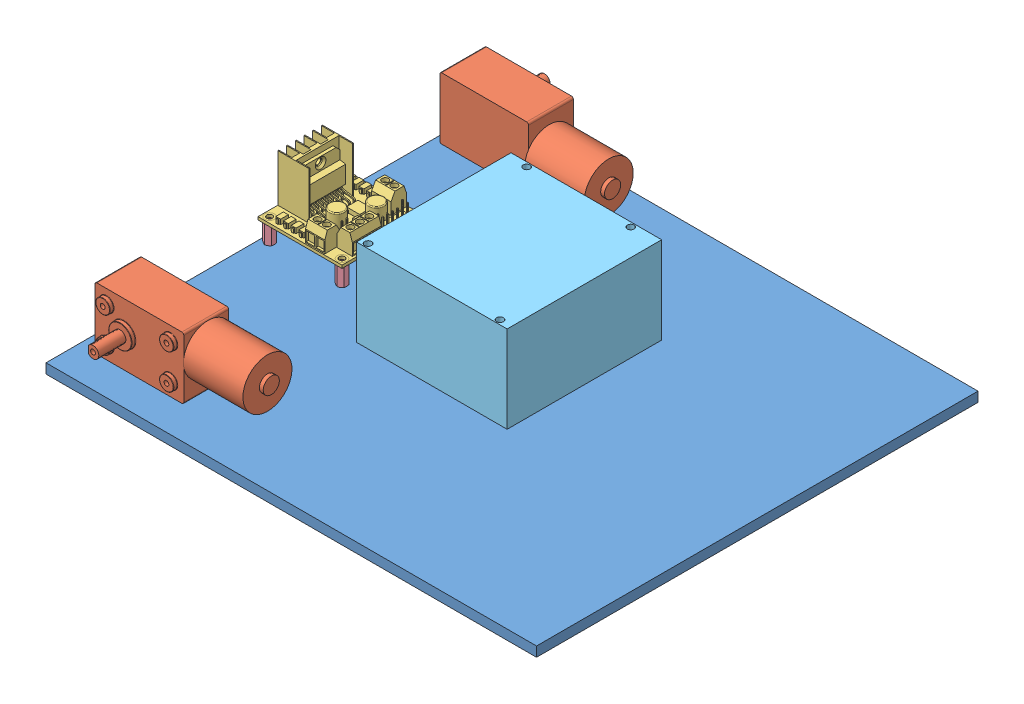
SolidWorks assembly robot, configuration Default. Lengths in mm.
Overall size (254 64.36 237.34).
9 component instances, 5 part files, 8 mates.
Components (placement in the parent):
- layer1-1: layer1 [Default] at (-140.5831 -10.1719 99.515) size (254 5.08 228.6)
- dc_motor-2: dc_motor [Default] at (-83.223 -2.1181 62.3196) x (0 1 0) z (1 0 0) size (32 41.21 78.8)
- dc_motor-3: dc_motor [Default] at (-86.8243 31.2472 -96.6224) x (0 -1 0) z (1 0 0) size (32 41.21 78.8)
- L298N Motor Driver-1: L298N Motor Driver [Default] at (-100.89 21.9991 -14.0592) x (0 0 1) z (-1 0 0) size (43.5 26 43.5)
- 94868A166_Female Threaded Hex Standoff-1: 94868A166_Female Threaded Hex Standoff [94868A166] at (-82.14 16.9991 -32.8092) x (1 0 0) z (0 1 0) size (4.5 5.2 10.38)
- 94868A166_Female Threaded Hex Standoff-2: 94868A166_Female Threaded Hex Standoff [94868A166] at (-119.64 16.9991 4.6908) x (1 0 0) z (0 1 0) size (4.5 5.2 10.38)
- 94868A166_Female Threaded Hex Standoff-3: 94868A166_Female Threaded Hex Standoff [94868A166] at (-82.14 16.9991 4.6908) x (1 0 0) z (0 1 0) size (4.5 5.2 10.38)
- 94868A166_Female Threaded Hex Standoff-4: 94868A166_Female Threaded Hex Standoff [94868A166] at (-119.64 16.9991 -32.8092) x (1 0 0) z (0 1 0) size (4.5 5.2 10.38)
- uno32_stack-1: uno32_stack [Default] at (-55.0798 9.1915 24.2345) size (78 45 80)
Mates (geometry in assembly coordinates):
- Concentric4: concentric: circle of L298N Motor Driver-1; circle of 94868A166_Female Threaded Hex Standoff-4
- Coincident6: coincident: plane of L298N Motor Driver-1 through (-100.89 21.9991 -14.0592) normal (0 -1 0); plane of 94868A166_Female Threaded Hex Standoff-4 through (-119.64 21.9991 -35.4073) normal (0 1 0)
- Concentric5: concentric: circle of L298N Motor Driver-1; circle of 94868A166_Female Threaded Hex Standoff-2
- Coincident7: coincident: plane of L298N Motor Driver-1 through (-100.89 21.9991 -14.0592) normal (0 -1 0); plane of 94868A166_Female Threaded Hex Standoff-2 through (-119.64 21.9991 2.0927) normal (0 1 0)
- Concentric6: concentric: circle of L298N Motor Driver-1; circle of 94868A166_Female Threaded Hex Standoff-3
- Coincident8: coincident: plane of L298N Motor Driver-1 through (-100.89 21.9991 -14.0592) normal (0 -1 0); plane of 94868A166_Female Threaded Hex Standoff-3 through (-82.14 21.9991 2.0927) normal (0 1 0)
- Concentric7: concentric: circle of L298N Motor Driver-1; circle of 94868A166_Female Threaded Hex Standoff-1
- Coincident9: coincident: plane of L298N Motor Driver-1 through (-100.89 21.9991 -14.0592) normal (0 -1 0); plane of 94868A166_Female Threaded Hex Standoff-1 through (-82.14 21.9991 -35.4073) normal (0 1 0)
